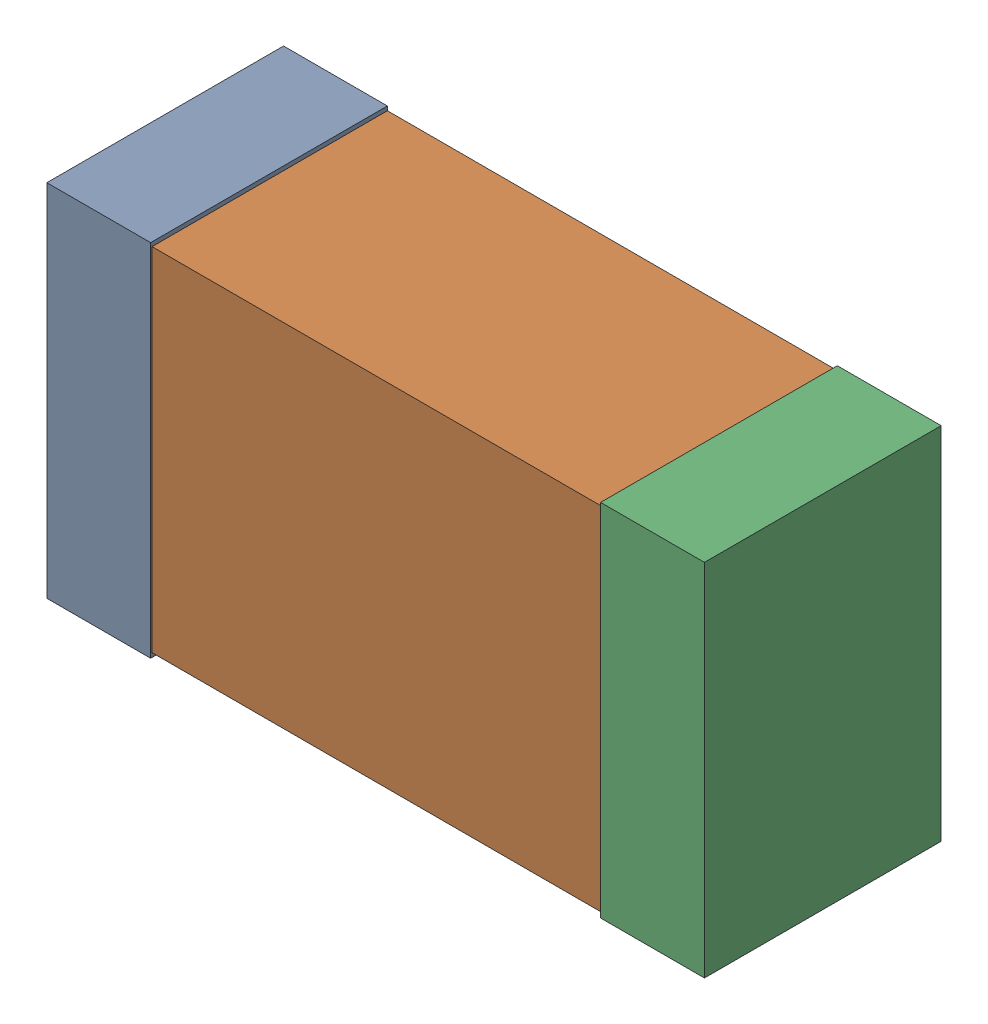
SolidWorks assembly 10kKanaloa_v2.0.0_Power_1, configuration Default. Lengths in mm.
Overall size (2.38 1.3 0.85).
6 component instances, 2 part files, 0 mates.
Components (placement in the parent):
- 352877648-1: 352877648 [Default] at (133.5068 88.1554 0) size (0.38 1.3 0.85)
  - Extruded_14-1: Extruded_14 [Default] at origin size (0.38 1.3 0.85)
- 352877392-1: 352877392 [Default] at (134.5068 88.1554 0) size (2.2 1.27 0.85)
  - Extruded_15-1: Extruded_15 [Default] at origin size (2.2 1.27 0.85)
- 352877648-2: 352877648 [Default] at (135.5068 88.1554 0) size (0.38 1.3 0.85)
  - Extruded_14-1: Extruded_14 [Default] at origin size (0.38 1.3 0.85)
